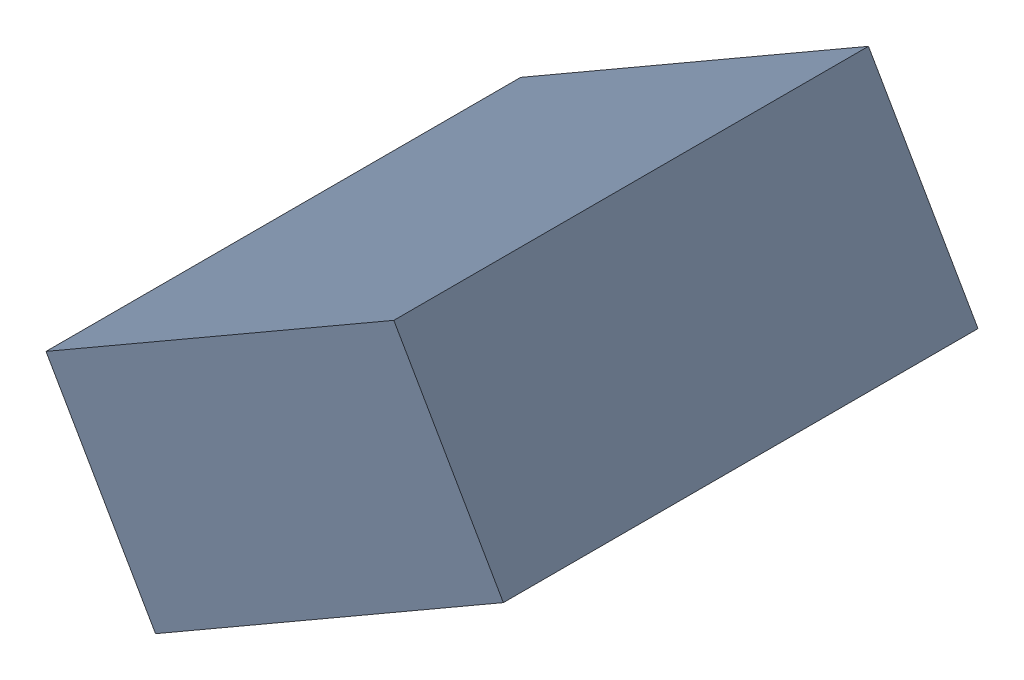
SolidWorks assembly C23_TDA5, configuration Standard. Lengths in mm.
Overall size (1.25 1.07 1.3).
2 component instances, 1 part files, 0 mates.
Components (placement in the parent):
- 885542920-1: 885542920 [Standard] at (-45.1166 -24.0316 0) size (1.25 1.07 1.3)
  - Extruded_24-1: Extruded_24 [Standard] at origin size (1.25 1.07 1.3)
